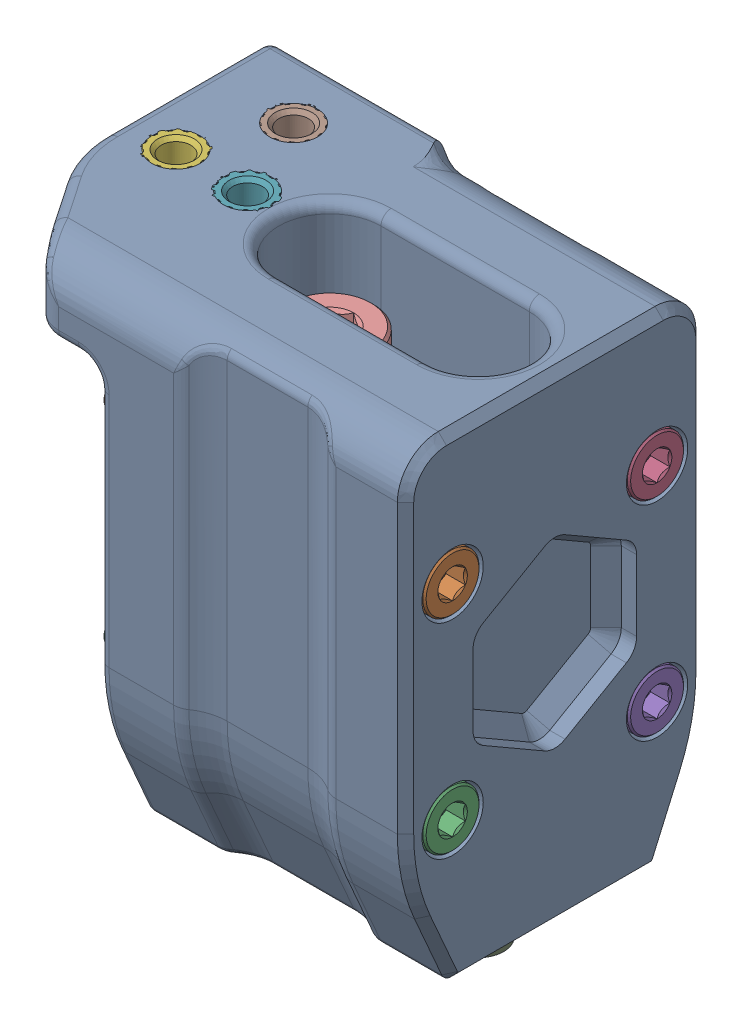
SolidWorks assembly Z Bearing Block - Right, configuration Default. Lengths in mm.
Overall size (42.7 52.1 29.31).
10 component instances, 4 part files, 0 mates.
Components (placement in the parent):
- Z Bearing Block - Right-1: Z Bearing Block - Right [Default] at origin size (42.55 46.91 29.31)
- M3x30 SHCS (4)-1: M3x30 SHCS (4) [Default] at (-138 25 171.9) x (0 0 1) z (-1 0 0) size (5.5 5.5 33.14)
- M3x30 SHCS (4)-2: M3x30 SHCS (4) [Default] at (-138 5 171.9) x (0 0 1) z (-1 0 0) size (5.5 5.5 33.14)
- M3x30 SHCS (4)-3: M3x30 SHCS (4) [Default] at (-138 25 151.9) x (0 0 1) z (-1 0 0) size (5.5 5.5 33.14)
- M3x30 SHCS (4)-4: M3x30 SHCS (4) [Default] at (-138 5 151.9) x (0 0 1) z (-1 0 0) size (5.5 5.5 33.14)
- M3 Threaded Insert (4)-1: M3 Threaded Insert (4) [Default] at (-142.5 33.95 161.45) x (1 0 0) z (0 1 0) size (5 5 3.85)
- M3 Threaded Insert (4)-2: M3 Threaded Insert (4) [Default] at (-135.5 33.95 161.45) x (1 0 0) z (0 1 0) size (5 5 3.85)
- M3 Threaded Insert (4)-3: M3 Threaded Insert (4) [Default] at (-139 33.95 153.45) x (1 0 0) z (0 1 0) size (5 5 3.85)
- M5x40 SHCS (2)-1: M5x40 SHCS (2) [Default] at (-112.5 -14.2 161.9) x (1 0 0) z (0 -1 0) size (8.5 8.5 45.23)
- M5x40 SHCS (2)-2: M5x40 SHCS (2) [Default] at (-127 -14.2 161.9) x (1 0 0) z (0 -1 0) size (8.5 8.5 45.23)
